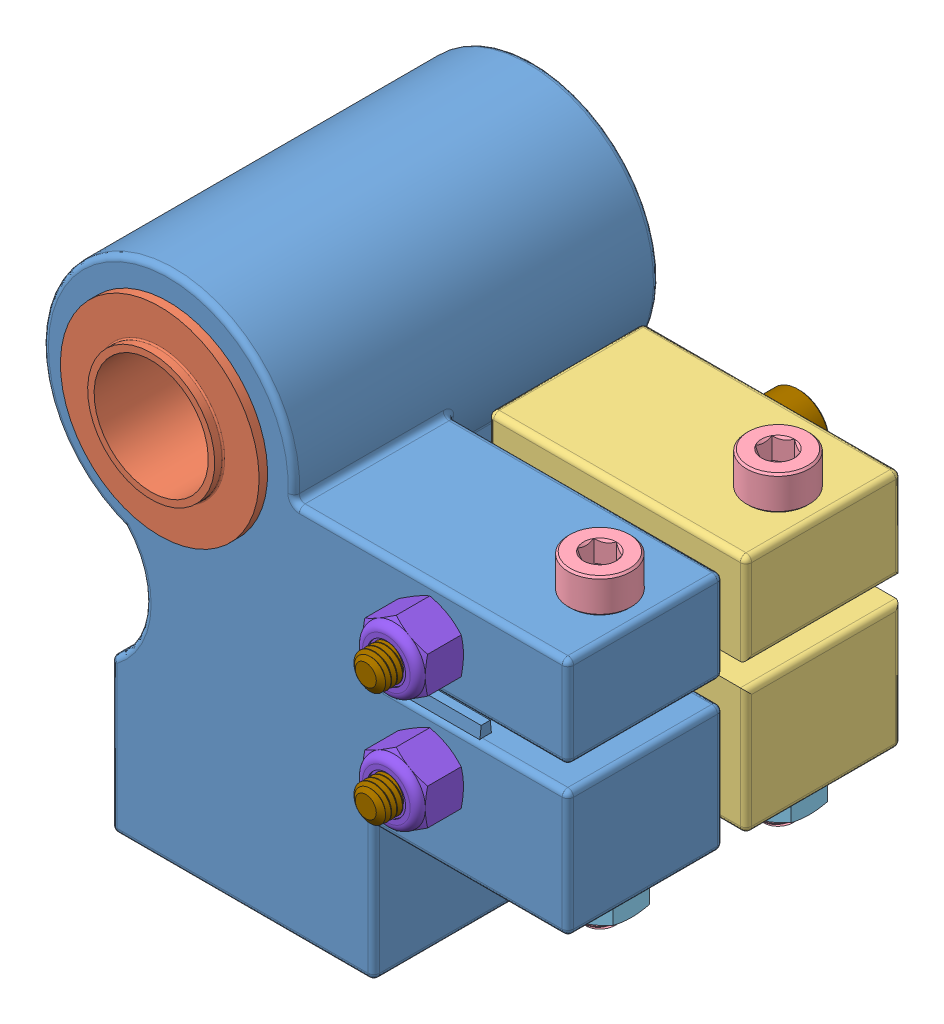
SolidWorks assembly XY_Axis_Belt_Tensioner_A, configuration Default. Lengths in mm.
Overall size (46 45 39.42).
14 component instances, 9 part files, 39 mates.
Components (placement in the parent):
- XY Axis Belt Tensioner A-1: XY Axis Belt Tensioner A [Default] at origin size (46 45 32.06)
- a_7z41mpsb10m-1: a_7z41mpsb10m [Default] at (5 34 16.75) x (1 0 0) z (0 1 0) size (17.4 11.55 17.4)
- a_7z41mpsb10m-2: a_7z41mpsb10m [Default] at (5 34 -16.75) x (1 0 0) z (0 -1 0) size (17.4 11.55 17.4)
- XY Axis Belt Tensioner End-1: XY Axis Belt Tensioner End [Default] at (0 0 -15.6) size (22.6 21 13.6)
- 3mmX25mm_Sockethead(McMaster_91290A125)-1: 3mmX25mm_Sockethead(McMaster_91290A125) [91290A125] at (36 7.85 -6.4) x (1 0 0) z (0 -1 0) size (5.5 5.5 28.26)
- 3mmX25mm_Sockethead(McMaster_91290A125)-2: 3mmX25mm_Sockethead(McMaster_91290A125) [91290A125] at (36 7.85 9.2) x (1 0 0) z (0 -1 0) size (5.5 5.5 28.26)
- 3mm_Hex_Nut(McMaster_90591A121)-1: 3mm_Hex_Nut(McMaster_90591A121) [90591A121] at (36 10.65 9.2) size (5.5 2.58 6.35)
- 3mm_Hex_Nut(McMaster_90591A121)-2: 3mm_Hex_Nut(McMaster_90591A121) [90591A121] at (36 10.65 -6.4) size (5.5 2.58 6.35)
- 5mmX16mm_Buttonhead(McMaster_91239A232)-1: 5mmX16mm_Buttonhead(McMaster_91239A232) [91239A232] at (8.7 3.25 -7.6) x (0.866025 0 -0.5) z (0 -1 0) size (9.5 9.5 19.24)
- 5mm_Hex_Nut(McMaster_90591A146)-1: 5mm_Hex_Nut(McMaster_90591A146) [90591A146] at (8.7 21.5 -7.6) x (0.5 0 -0.866025) z (0.866025 0 0.5) size (8 4.31 9.24)
- 3mm_Hex_Nylock_Nut(McMaster_90576A102)-1: 3mm_Hex_Nylock_Nut(McMaster_90576A102) [90576A102] at (28.1 18.85 16) x (0.5 -0.866025 0) z (-0.866025 -0.5 0) size (5.5 4.1 6.35)
- 3mm_Hex_Nylock_Nut(McMaster_90576A102)-2: 3mm_Hex_Nylock_Nut(McMaster_90576A102) [90576A102] at (28.1 28.85 16) x (0.5 -0.866025 0) z (-0.866025 -0.5 0) size (5.5 4.1 6.35)
- 3mmX35mm_Sockethead(McMaster_91290A135)-1: 3mmX35mm_Sockethead(McMaster_91290A135) [91290A135] at (28.1 28.85 21.8) x (0.5 0.866025 0) z (0 0 1) size (5.5 5.5 38.26)
- 3mmX35mm_Sockethead(McMaster_91290A135)-2: 3mmX35mm_Sockethead(McMaster_91290A135) [91290A135] at (28.1 18.85 21.8) x (0.5 0.866025 0) z (0 0 1) size (5.5 5.5 38.26)
Mates (geometry in assembly coordinates):
- Concentric1: concentric aligned: cylinder of XY Axis Belt Tensioner A-1 through (5 34 5) axis (0 0 1) radius 7.95; circle of a_7z41mpsb10m-1
- Coincident1: coincident anti-aligned: plane of XY Axis Belt Tensioner A-1 through (-4 19 16) normal (0 0 1); plane of a_7z41mpsb10m-1 through (5 34 16) normal (0 0 -1)
- Concentric2: concentric aligned: cylinder of XY Axis Belt Tensioner A-1 through (5 34 -5) axis (0 0 -1) radius 7.95; circle of a_7z41mpsb10m-2
- Coincident2: coincident anti-aligned: plane of XY Axis Belt Tensioner A-1 through (-4 19 -16) normal (0 0 -1); plane of a_7z41mpsb10m-2 through (5 34 -16) normal (0 0 1)
- Concentric322: concentric aligned: cylinder of XY Axis Belt Tensioner A-1 through (28.1 28.85 16) axis (0 0 -1) radius 1.6; cylinder of XY Axis Belt Tensioner End-1 through (28.1 28.85 0.4) axis (0 0 -1) radius 1.6
- Concentric323: concentric aligned: cylinder of XY Axis Belt Tensioner A-1 through (28.1 18.85 16) axis (0 0 -1) radius 1.6; cylinder of XY Axis Belt Tensioner End-1 through (28.1 18.85 0.4) axis (0 0 -1) radius 1.6
- Distance1: distance = 2 mm anti-aligned: plane of XY Axis Belt Tensioner End-1 through (-4 19 0.4) normal (0 0 1); plane of XY Axis Belt Tensioner A-1 through (0 0 2.4) normal (0 0 -1)
- Concentric326: concentric aligned: cylinder of XY Axis Belt Tensioner A-1 through (8.7 25 -7.6) axis (0 -1 0) radius 2.6; cylinder of 5mmX16mm_Buttonhead(McMaster_91239A232)-1 through (8.7 3.25 -7.6) axis (0 -1 0) radius 4.75
- Coincident323: coincident anti-aligned: plane of XY Axis Belt Tensioner A-1 through (8.7 6 -7.6) normal (0 -1 0); plane of 5mmX16mm_Buttonhead(McMaster_91239A232)-1 through (6.325 6 -11.7136) normal (0 1 0)
- Concentric327: concentric anti-aligned: cylinder of XY Axis Belt Tensioner A-1 through (36 7.3245 9.2) axis (0 1 0) radius 1.6; cylinder of 3mmX25mm_Sockethead(McMaster_91290A125)-2 through (36 32.85 9.2) axis (0 -1 0) radius 1.5
- Concentric328: concentric anti-aligned: cylinder of XY Axis Belt Tensioner End-1 through (36 7.3245 -6.4) axis (0 1 0) radius 1.6; cylinder of 3mmX25mm_Sockethead(McMaster_91290A125)-1 through (36 32.85 -6.4) axis (0 -1 0) radius 1.5
- Coincident324: coincident anti-aligned: plane of XY Axis Belt Tensioner A-1 through (40 32.85 16) normal (0 1 0); plane of 3mmX25mm_Sockethead(McMaster_91290A125)-2 through (36 32.85 9.2) normal (0 -1 0)
- Coincident325: coincident anti-aligned: plane of XY Axis Belt Tensioner End-1 through (40 32.85 0.4) normal (0 1 0); plane of 3mmX25mm_Sockethead(McMaster_91290A125)-1 through (36 32.85 -6.4) normal (0 -1 0)
- Concentric329: concentric anti-aligned: cylinder of XY Axis Belt Tensioner A-1 through (28.1 28.85 16) axis (0 0 -1) radius 1.6; cylinder of 3mmX35mm_Sockethead(McMaster_91290A135)-1 through (28.1 28.85 -13.2) axis (0 0 1) radius 1.5
- Concentric330: concentric anti-aligned: cylinder of XY Axis Belt Tensioner A-1 through (28.1 18.85 16) axis (0 0 -1) radius 1.6; cylinder of 3mmX35mm_Sockethead(McMaster_91290A135)-2 through (28.1 18.85 -13.2) axis (0 0 1) radius 1.5
- Coincident328: coincident anti-aligned: plane of XY Axis Belt Tensioner End-1 through (0 0 -13.2) normal (0 0 -1); plane of 3mmX35mm_Sockethead(McMaster_91290A135)-1 through (28.1 28.85 -13.2) normal (0 0 1)
- Coincident329: coincident anti-aligned: plane of XY Axis Belt Tensioner End-1 through (0 0 -13.2) normal (0 0 -1); plane of 3mmX35mm_Sockethead(McMaster_91290A135)-2 through (28.1 18.85 -13.2) normal (0 0 1)
- Concentric331: concentric anti-aligned: cylinder of 3mm_Hex_Nylock_Nut(McMaster_90576A102)-2 through (28.1 28.85 19.4095) axis (0 0 -1) radius 1.269; cylinder of 3mmX35mm_Sockethead(McMaster_91290A135)-1 through (28.1 28.85 -13.2) axis (0 0 1) radius 1.5
- Concentric332: concentric anti-aligned: cylinder of 3mm_Hex_Nylock_Nut(McMaster_90576A102)-1 through (28.1 18.85 19.4095) axis (0 0 -1) radius 1.269; cylinder of 3mmX35mm_Sockethead(McMaster_91290A135)-2 through (28.1 18.85 -13.2) axis (0 0 1) radius 1.5
- Coincident330: coincident anti-aligned: plane of XY Axis Belt Tensioner A-1 through (-4 19 16) normal (0 0 1); plane of 3mm_Hex_Nylock_Nut(McMaster_90576A102)-2 through (30.85 30.4377 16) normal (0 0 -1)
- Coincident331: coincident anti-aligned: plane of XY Axis Belt Tensioner A-1 through (-4 19 16) normal (0 0 1); plane of 3mm_Hex_Nylock_Nut(McMaster_90576A102)-1 through (30.85 20.4377 16) normal (0 0 -1)
- Concentric333: concentric aligned: cylinder of XY Axis Belt Tensioner A-1 through (8.7 25 -7.6) axis (0 -1 0) radius 2.6; circle of 5mm_Hex_Nut(McMaster_90591A146)-1
- Coincident332: coincident anti-aligned: plane of XY Axis Belt Tensioner A-1 through (12.725 19.5 -1.1) normal (0 1 0); plane of 5mm_Hex_Nut(McMaster_90591A146)-1 through (0.7 19.5 -7.6) normal (0 -1 0)
- Parallel12: parallel anti-aligned: plane of XY Axis Belt Tensioner A-1 through (4.675 23.5 -1.1) normal (1 0 0); plane of 5mm_Hex_Nut(McMaster_90591A146)-1 through (4.7 23.5 -9.9094) normal (-1 0 0)
- Parallel1: parallel aligned: plane of XY Axis Belt Tensioner A-1 through (40 24.85 16) normal (1 0 0); plane of 3mm_Hex_Nylock_Nut(McMaster_90576A102)-2 through (30.85 27.2623 20) normal (1 0 0)
- Parallel2: parallel aligned: plane of XY Axis Belt Tensioner A-1 through (40 11.85 16) normal (1 0 0); plane of 3mm_Hex_Nylock_Nut(McMaster_90576A102)-1 through (30.85 17.2623 20) normal (1 0 0)
- Parallel3: parallel aligned: plane of XY Axis Belt Tensioner A-1 through (40 24.85 16) normal (1 0 0); plane of 3mmX35mm_Sockethead(McMaster_91290A135)-1 through (26.85 28.1283 -14.325) normal (1 0 0)
- Parallel4: parallel aligned: plane of XY Axis Belt Tensioner A-1 through (40 11.85 16) normal (1 0 0); plane of 3mmX35mm_Sockethead(McMaster_91290A135)-2 through (26.85 18.1283 -14.325) normal (1 0 0)
- Coincident338: coincident aligned: cylinder of 3mmX25mm_Sockethead(McMaster_91290A125)-1 through (36 32.85 -6.4) axis (0 -1 0) radius 1.5; circle of 3mm_Hex_Nut(McMaster_90591A121)-2
- Coincident339: coincident aligned: cylinder of 3mmX25mm_Sockethead(McMaster_91290A125)-2 through (36 32.85 9.2) axis (0 -1 0) radius 1.5; circle of 3mm_Hex_Nut(McMaster_90591A121)-1
- Coincident340: coincident anti-aligned: plane of XY Axis Belt Tensioner A-1 through (23 11.85 16) normal (0 -1 0); plane of 3mm_Hex_Nut(McMaster_90591A121)-1 through (38.75 11.85 7.6123) normal (0 1 0)
- Coincident341: coincident anti-aligned: plane of XY Axis Belt Tensioner End-1 through (23 11.85 0.4) normal (0 -1 0); plane of 3mm_Hex_Nut(McMaster_90591A121)-2 through (38.75 11.85 -7.9877) normal (0 1 0)
- Parallel5: parallel aligned: plane of XY Axis Belt Tensioner End-1 through (40 11.85 0.4) normal (1 0 0); plane of 3mm_Hex_Nut(McMaster_90591A121)-2 through (38.75 11.85 -4.8123) normal (1 0 0)
- Parallel6: parallel aligned: plane of XY Axis Belt Tensioner A-1 through (40 11.85 16) normal (1 0 0); plane of 3mm_Hex_Nut(McMaster_90591A121)-1 through (38.75 11.85 10.7877) normal (1 0 0)
- Parallel7: parallel aligned: plane of XY Axis Belt Tensioner A-1 through (-4 19 -16) normal (0 0 -1); plane of 5mmX16mm_Buttonhead(McMaster_91239A232)-1 through (9.566 5.175 -6.1) normal (0 0 -1)
- Parallel8: parallel aligned: plane of XY Axis Belt Tensioner End-1 through (40 24.85 0.4) normal (1 0 0); plane of 3mmX25mm_Sockethead(McMaster_91290A125)-1 through (34.75 33.975 -7.1217) normal (1 0 0)
- Parallel9: parallel aligned: plane of XY Axis Belt Tensioner A-1 through (40 24.85 16) normal (1 0 0); plane of 3mmX25mm_Sockethead(McMaster_91290A125)-2 through (34.75 33.975 8.4783) normal (1 0 0)
- Parallel10: parallel aligned: plane of XY Axis Belt Tensioner A-1 through (40 32.85 16) normal (0 1 0); plane of a_7z41mpsb10m-1 through (5 34 16.75) normal (0 1 0)
- Parallel11: parallel anti-aligned: plane of XY Axis Belt Tensioner A-1 through (40 32.85 16) normal (0 1 0); plane of a_7z41mpsb10m-2 through (5 34 -16.75) normal (0 -1 0)
